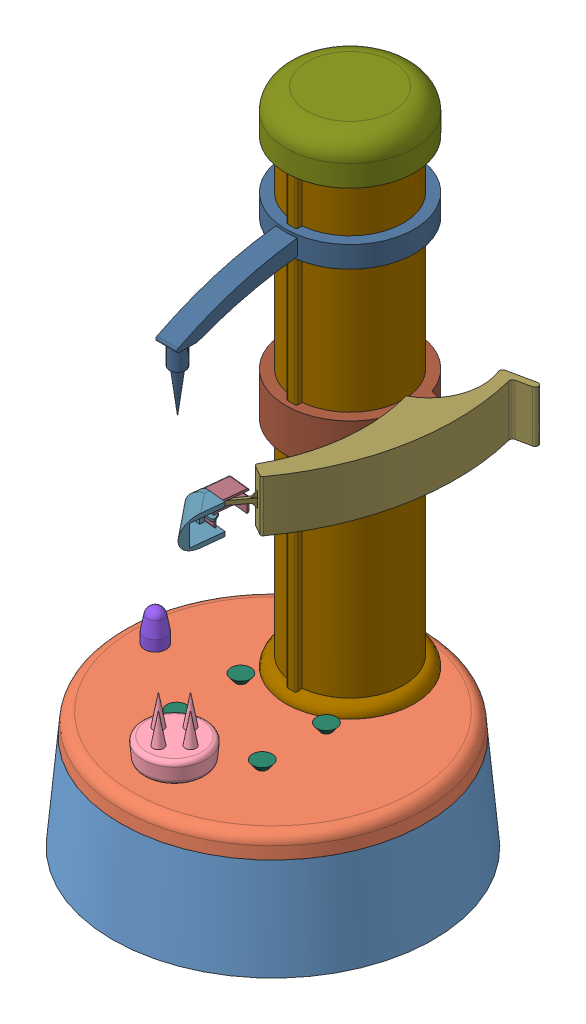
SolidWorks assembly DFA-FINAL-ASSEMBLY, configuration Default. Lengths in mm.
Overall size (150 290 150).
21 component instances, 16 part files, 26 mates.
Components (placement in the parent):
- dfa-Base-1: dfa-Base [Default] at (42.4494 55.4034 122.5382) size (150 45 150)
- dfa-Base-Lid-packandgo-1: dfa-Base-Lid-packandgo [Default] at (42.4494 100.4034 122.5382) size (142.1 20.5 142.1)
- dfa-battery-placeholder-packandgo-1: dfa-battery-placeholder-packandgo [Default] at (-11.1919 75.3858 98.0058) size (24.1 24.1 50)
- dfa-bottomfood-holder-packandgo-1: dfa-bottomfood-holder-packandgo [Default] at (42.4494 123.4034 168.5882) size (29.63 24.18 29.63)
- dfa-gearbox-placeholder-packandgo-1: dfa-gearbox-placeholder-packandgo [Default] at (12.4494 83.4034 180.0382) size (60 35 115)
- dfa-lead-screw-shaft-placeholder-packandgo-1: dfa-lead-screw-shaft-placeholder-packandgo [Default] at (42.4494 88.4034 86.4882) size (15 225 15)
- dfa-motor placeholder-packandgo-1: dfa-motor placeholder-packandgo [Default] at (42.4494 60.4034 122.5382) size (40 37.5 40)
- dfa-power-button-packandgo-1: dfa-power-button-packandgo [Default] at (-12.5506 115.4034 122.5382) size (10 20 10)
- dfa-shaft-1: dfa-shaft [Default] at (42.4494 110.4034 86.4882) size (60 230 60)
- dfa-upper-food-holder-packandgo-1: dfa-upper-food-holder-packandgo [Default] at (42.4494 292.5777 86.4882) size (60 50 115.86)
- test-peeler-assembly-packandgo-1: test-peeler-assembly-packandgo [Default] at (42.911 198.761 93.1685) size (86.25 24 133.37)
  - peeler-arm-holder-packandgo-1: peeler-arm-holder-packandgo [Default] at (-0.4616 12.3778 -6.6803) size (67.27 20 60)
  - peeler-armSLDPRT-packandgo-1: peeler-armSLDPRT-packandgo [Default] at (-0.4494 10.3778 -5.781) x (0.999629 0 -0.027252) z (0.027252 0 0.999629) size (44.16 24 111.93)
  - test-blade-packandgo-1: test-blade-packandgo [Default] at (4.0402 13.5549 73.6494) x (0.999844 0 0.017689) z (-0.017689 0 0.999844) size (16.7 14 34.06)
    - blade-holder-arm-packandgo-1: blade-holder-arm-packandgo [Default] at (0.5593 0.8229 -2.6525) x (0.996145 0 0.087727) z (-0.087727 0 0.996145) size (10 10 15)
    - blade-holder-packandgo-2: blade-holder-packandgo [Default] at (14.1842 5.8229 -3.4604) x (0.087727 0 -0.996145) z (0 1 0) size (20 15 14)
- philips-10-24-0.75-placeholder-packandgo-1: philips-10-24-0.75-placeholder-packandgo [Default] at (20.0364 110.4034 147.5382) x (0 -1 0) z (0 0 1) size (19.05 9.19 9.19)
- philips-10-24-0.75-placeholder-packandgo-2: philips-10-24-0.75-placeholder-packandgo [Default] at (60.0364 110.4034 147.5382) x (0 -1 0) z (0 0 1) size (19.05 9.19 9.19)
- philips-10-24-0.75-placeholder-packandgo-3: philips-10-24-0.75-placeholder-packandgo [Default] at (60.0364 110.4034 117.5382) x (0 -1 0) z (0 0 1) size (19.05 9.19 9.19)
- philips-10-24-0.75-placeholder-packandgo-4: philips-10-24-0.75-placeholder-packandgo [Default] at (20.0364 110.4034 117.5382) x (0 -1 0) z (0 0 1) size (19.05 9.19 9.19)
- cap-packandgo-1: cap-packandgo [Default] at (42.4494 325.4034 86.4882) x (0.999979 0 -0.006538) z (0.006538 0 0.999979) size (60 20 60)
Mates (geometry in assembly coordinates):
- Coincident2: coincident anti-aligned: plane of dfa-gearbox-placeholder-packandgo-1 through (42.4494 97.9034 122.5382) normal (0 -1 0); plane of dfa-motor placeholder-packandgo-1 through (42.4494 97.9034 122.5382) normal (0 1 0)
- Concentric1: concentric aligned: cylinder of dfa-gearbox-placeholder-packandgo-1 through (42.4494 97.9034 122.5382) axis (0 -1 0) radius 5; cylinder of dfa-motor placeholder-packandgo-1 through (42.4494 97.9034 122.5382) axis (0 -1 0) radius 5
- Coincident4: coincident anti-aligned: plane of dfa-bottomfood-holder-packandgo-1 through (42.4494 118.4034 168.5882) normal (0 -1 0); plane of dfa-gearbox-placeholder-packandgo-1 through (42.4494 118.4034 168.5882) normal (0 1 0)
- Concentric2: concentric aligned: cylinder of dfa-bottomfood-holder-packandgo-1 through (42.4494 118.4034 168.5882) axis (0 -1 0) radius 5; cylinder of dfa-gearbox-placeholder-packandgo-1 through (42.4494 118.4034 168.5882) axis (0 -1 0) radius 4.75
- Coincident5: coincident anti-aligned: plane of dfa-Base-1 through (42.4494 60.4034 122.5382) normal (0 1 0); plane of dfa-motor placeholder-packandgo-1 through (42.4494 60.4034 122.5382) normal (0 -1 0)
- Concentric3: concentric anti-aligned: cylinder of dfa-Base-Lid-packandgo-1 through (42.4494 100.4034 168.5882) axis (0 1 0) radius 5; cylinder of dfa-gearbox-placeholder-packandgo-1 through (42.4494 118.4034 168.5882) axis (0 -1 0) radius 4.75
- Coincident6: coincident anti-aligned: plane of dfa-Base-1 through (42.4494 100.4034 122.5382) normal (0 1 0); plane of dfa-Base-Lid-packandgo-1 through (42.4494 100.4034 122.5382) normal (0 -1 0)
- Concentric4: concentric aligned: circle of dfa-Base-1; circle of dfa-Base-Lid-packandgo-1
- Coincident7: coincident aligned: circle of dfa-gearbox-placeholder-packandgo-1; circle of dfa-lead-screw-shaft-placeholder-packandgo-1
- Concentric6: concentric aligned: cylinder of dfa-lead-screw-shaft-placeholder-packandgo-1 through (42.4494 313.4034 86.4882) axis (0 -1 0) radius 7.5; cylinder of test-peeler-assembly-packandgo-1/peeler-arm-holder-packandgo-1 through (42.4494 231.1388 86.4882) axis (0 -1 0) radius 7.5
- Coincident8: coincident anti-aligned: plane of dfa-Base-Lid-packandgo-1 through (42.4494 110.4034 122.5382) normal (0 1 0); plane of dfa-shaft-1 through (42.4494 110.4034 86.4882) normal (0 -1 0)
- Coincident9: coincident anti-aligned: circle of dfa-Base-Lid-packandgo-1; circle of dfa-shaft-1
- Concentric7: concentric anti-aligned: cylinder of dfa-shaft-1 through (42.4494 105.4034 86.4882) axis (0 1 0) radius 20; cylinder of dfa-upper-food-holder-packandgo-1 through (42.4494 302.5777 86.4882) axis (0 -1 0) radius 25
- Coincident10: coincident aligned: circle of dfa-Base-Lid-packandgo-1; circle of dfa-power-button-packandgo-1
- Concentric8: concentric anti-aligned: cylinder of dfa-Base-Lid-packandgo-1 through (62.4494 100.4034 147.5382) axis (0 1 0) radius 2.413; cylinder of philips-10-24-0.75-placeholder-packandgo-2 through (62.4494 88.2385 147.5382) axis (0 -1 0) radius 2.413
- Concentric9: concentric anti-aligned: cylinder of dfa-Base-Lid-packandgo-1 through (62.4494 100.4034 117.5382) axis (0 1 0) radius 2.413; cylinder of philips-10-24-0.75-placeholder-packandgo-3 through (62.4494 88.2385 117.5382) axis (0 -1 0) radius 2.413
- Concentric11: concentric anti-aligned: cylinder of dfa-Base-Lid-packandgo-1 through (22.4494 100.4034 147.5382) axis (0 1 0) radius 2.413; cylinder of philips-10-24-0.75-placeholder-packandgo-1 through (22.4494 88.2385 147.5382) axis (0 -1 0) radius 2.413
- Concentric12: concentric anti-aligned: cylinder of dfa-Base-Lid-packandgo-1 through (22.4494 100.4034 117.5382) axis (0 1 0) radius 2.413; cylinder of philips-10-24-0.75-placeholder-packandgo-4 through (22.4494 88.2385 117.5382) axis (0 -1 0) radius 2.413
- Coincident11: coincident anti-aligned: plane of dfa-Base-Lid-packandgo-1 through (42.4494 110.4034 122.5382) normal (0 1 0); circle of philips-10-24-0.75-placeholder-packandgo-1
- Coincident12: coincident anti-aligned: plane of dfa-Base-Lid-packandgo-1 through (42.4494 110.4034 122.5382) normal (0 1 0); circle of philips-10-24-0.75-placeholder-packandgo-4
- Coincident13: coincident anti-aligned: plane of dfa-Base-Lid-packandgo-1 through (42.4494 110.4034 122.5382) normal (0 1 0); circle of philips-10-24-0.75-placeholder-packandgo-2
- Coincident14: coincident anti-aligned: plane of dfa-Base-Lid-packandgo-1 through (42.4494 110.4034 122.5382) normal (0 1 0); circle of philips-10-24-0.75-placeholder-packandgo-3
- Concentric13: concentric anti-aligned: cylinder of dfa-shaft-1 through (42.4494 105.4034 86.4882) axis (0 1 0) radius 25; cylinder of cap-packandgo-1 through (42.4494 335.4034 86.4882) axis (0 -1 0) radius 25
- Coincident15: coincident anti-aligned: plane of dfa-shaft-1 through (42.4494 335.4034 86.4882) normal (0 1 0); plane of cap-packandgo-1 through (42.4494 335.4034 86.4882) normal (0 -1 0)
- Coincident16: coincident anti-aligned: plane of dfa-shaft-1 through (40.9494 105.4034 113.9882) normal (0 0 1); plane of dfa-upper-food-holder-packandgo-1 through (42.4494 302.5777 113.9882) normal (0 0 -1)
- Coincident17: coincident anti-aligned: plane of dfa-shaft-1; plane of test-peeler-assembly-packandgo-1/peeler-arm-holder-packandgo-1 through (42.4494 231.1388 113.9882) normal (0 0 -1)
